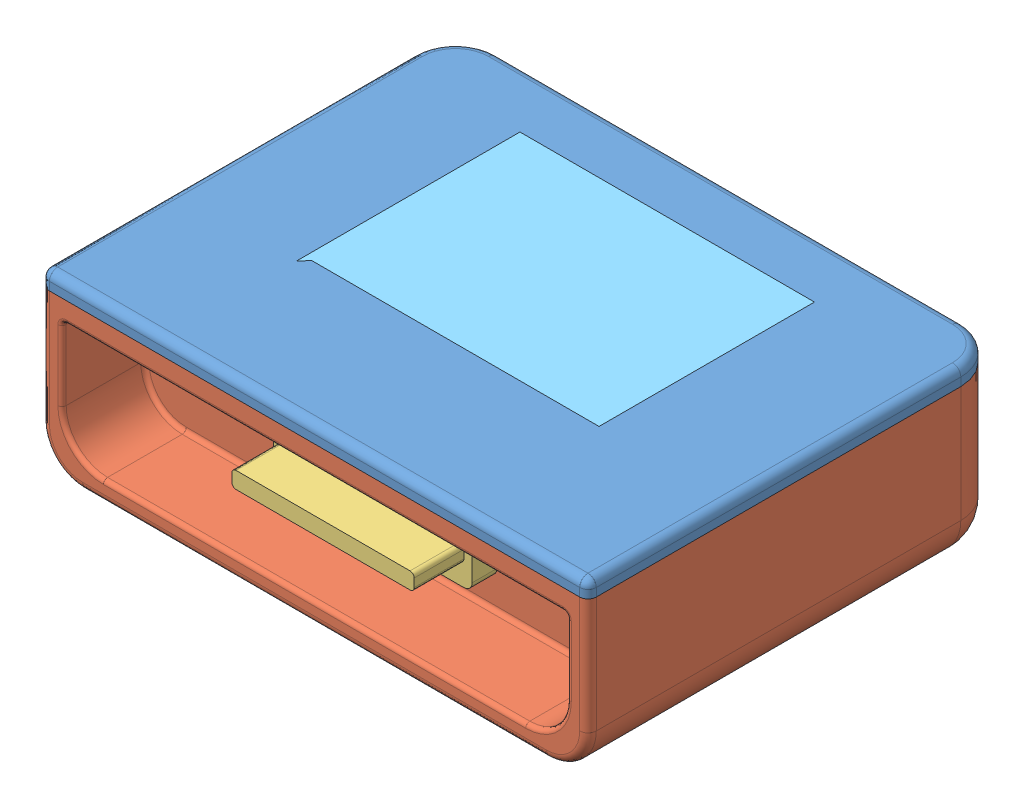
SolidWorks assembly exploded, configuration Default. Lengths in mm.
Overall size (66 21 51).
5 component instances, 5 part files, 16 mates.
Components (placement in the parent):
- cover board-1: cover board [Default] at (-10.4586 0.4753 9.9834) size (66 12 50)
- cover casing-1: cover casing [Default] at (-10.4586 0.4753 9.9834) size (66 19 50)
- pcb-1: pcb [Default] at (18.5631 2.9753 -26.0167) x (-1 0 0.000011) z (0.000011 0 1) size (58 14.5 50)
- lcd display-1: lcd display [Default] at (-32.2308 8.4753 -25.5626) size (34.54 2 25.91)
- transparent lid-1: transparent lid [Default] at (-32.2308 9.1753 -25.5626) size (43.67 1.8 33)
Mates (geometry in assembly coordinates):
- Concentric1: concentric anti-aligned: cylinder of cover board-1; cylinder of pcb-1
- Concentric2: concentric anti-aligned: cylinder of cover board-1; cylinder of pcb-1
- Coincident1: coincident anti-aligned: plane of cover board-1 through (16.5414 2.9753 0.9834) normal (0 -1 0); plane of pcb-1 through (18.5634 2.9753 5.9833) normal (0 1 0)
- Concentric3: concentric aligned: cylinder of cover board-1; cylinder of cover casing-1
- Concentric4: concentric aligned: cylinder of cover board-1; cylinder of cover casing-1
- Coincident2: coincident anti-aligned: plane of cover board-1 through (-45.0476 8.9753 -30.0166) normal (0 -1 0); plane of cover casing-1 through (-45.0476 8.9753 -30.0166) normal (0 1 0)
- Parallel1: parallel anti-aligned: line of cover board-1; line of transparent lid-1
- Parallel2: parallel anti-aligned: line of cover board-1; line of transparent lid-1
- Parallel3: parallel aligned: line of lcd display-1; line of transparent lid-1
- Parallel4: parallel anti-aligned: line of lcd display-1; line of transparent lid-1
- Coincident21: coincident anti-aligned: plane of lcd display-1 through (-32.2308 10.4753 6.4374) normal (0 1 0); plane of transparent lid-1 through (-28.1693 10.4753 3.3914) normal (0 -1 0)
- Coincident22: coincident anti-aligned: plane of lcd display-1 through (-28.1693 8.4753 3.3914) normal (0 0 1); plane of transparent lid-1 through (-28.1693 10.4753 3.3914) normal (0 0 -1)
- Coincident23: coincident anti-aligned: plane of lcd display-1 through (-28.1693 8.4753 -22.5166) normal (-1 0 0); plane of transparent lid-1 through (-28.1693 10.4753 -22.5166) normal (1 0 0)
- Coincident24: coincident anti-aligned: plane of cover board-1 through (6.8747 10.9763 2.9834) normal (-1 0 0); plane of transparent lid-1 through (6.8747 10.4753 -22.5166) normal (1 0 0)
- Coincident25: coincident anti-aligned: plane of cover board-1 through (6.8747 10.9763 -23.0166) normal (0 0 1); plane of transparent lid-1 through (-28.1693 10.4753 -23.0166) normal (0 0 -1)
- Coincident26: coincident aligned: unknown of ?; unknown of transparent lid-1
